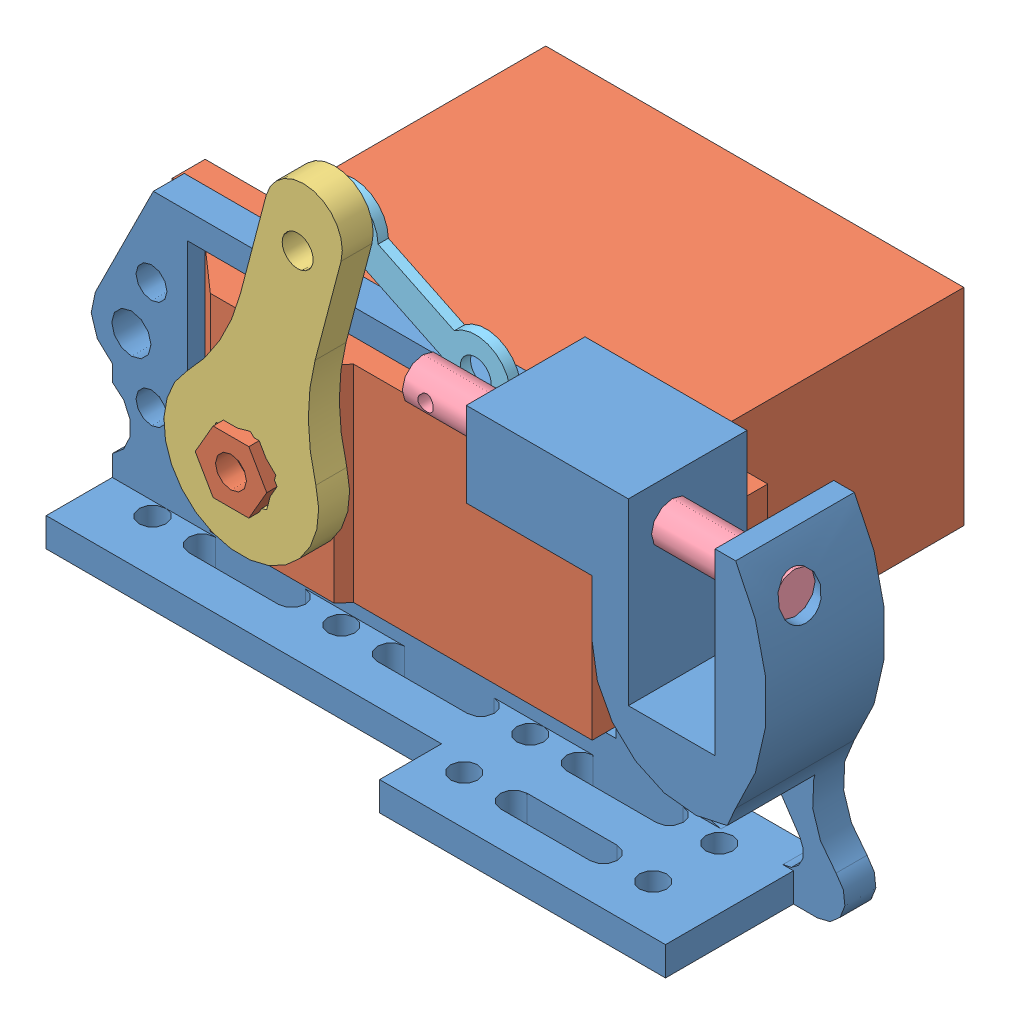
SolidWorks assembly assembly of release mech, configuration Default. Lengths in mm.
Overall size (73.95 44.3 46.6).
5 component instances, 5 part files, 9 mates.
Components (placement in the parent):
- servo holder-1: servo holder [Default] at (-22.1697 -12.9083 -9.928) size (73.95 34.5 15.4)
- Servo light-1: Servo light [Default] at (18.8303 -12.4083 -41.128) x (0 0 -1) z (1 0 0) size (41 20 54.5)
- servo arm light-1: servo arm light [Default] at (-11.1697 -2.4083 -4.128) x (0.967163 -0.254156 0) z (0 0 1) size (15 35 3)
- Pin-1: Pin [Default] at (40.8781 12.1917 -2.678) x (0 0 1) z (0 -1 0) size (4 36 4)
- part that looks like that thing on a train-1: part that looks like that thing on a train [Default] at (7.1281 12.1917 -6.5389) x (0.900591 -0.434667 0) z (-0.434667 -0.900591 0) size (21 1 6.75)
Mates (geometry in assembly coordinates):
- Width1: width anti-aligned: plane of Servo light-1 through (18.8303 7.5917 -15.128) normal (1 0 0); plane of servo holder-1 through (-21.6697 7.5917 -41.128) normal (-1 0 0); plane of Servo light-1 through (19.3303 -12.9083 -6.928) normal (-1 0 0); plane of servo holder-1 through (-22.1697 -12.9083 -6.928) normal (1 0 0)
- Width2: width anti-aligned: plane of Servo light-1 through (18.8303 7.5917 -41.128) normal (0 1 0); plane of servo holder-1 through (18.8303 -12.4083 -41.128) normal (0 -1 0); plane of Servo light-1 through (-22.1697 8.0917 -6.928) normal (0 -1 0); plane of servo holder-1 through (-22.1697 -12.9083 -6.928) normal (0 1 0)
- Distance1: distance = 2 mm anti-aligned: plane of Servo light-1 through (-28.6697 7.5917 -11.928) normal (0 0 1); plane of servo holder-1 through (11.3303 12.5917 -9.928) normal (0 0 -1)
- Coincident4: coincident anti-aligned: line of Servo light-1 through (-11.1697 -2.4083 -2.128) axis (0 0 1); line of servo arm light-1 through (-11.1697 -2.4083 -1.128) axis (0 0 -1)
- Coincident6: coincident anti-aligned: plane of Servo light-1 through (-17.1697 7.5917 -4.128) normal (0 0 1); plane of servo arm light-1 through (-5.1335 20.5618 -4.128) normal (0 0 -1)
- Concentric1: concentric anti-aligned: cylinder of servo holder-1 through (55.7303 12.1917 -2.678) axis (-1 0 0) radius 2; cylinder of Pin-1 through (4.8781 12.1917 -2.678) axis (1 0 0) radius 2
- Parallel1: parallel: plane of servo holder-1 through (-25.4911 10.5917 -6.928) normal (0 1 0); line of Pin-1 through (7.1281 12.1917 -4.532) axis (0 0 1)
- Coincident8: coincident anti-aligned: line of servo arm light-1 through (-5.7053 18.3857 -4.128) axis (0 0 1); line of part that looks like that thing on a train-1 through (-5.7053 18.3857 -5.5389) axis (0 0 -1)
- Coincident9: coincident anti-aligned: line of Pin-1 through (7.1281 12.1917 -4.532) axis (0 0 1); line of part that looks like that thing on a train-1 through (7.1281 12.1917 -5.5389) axis (0 0 -1)
